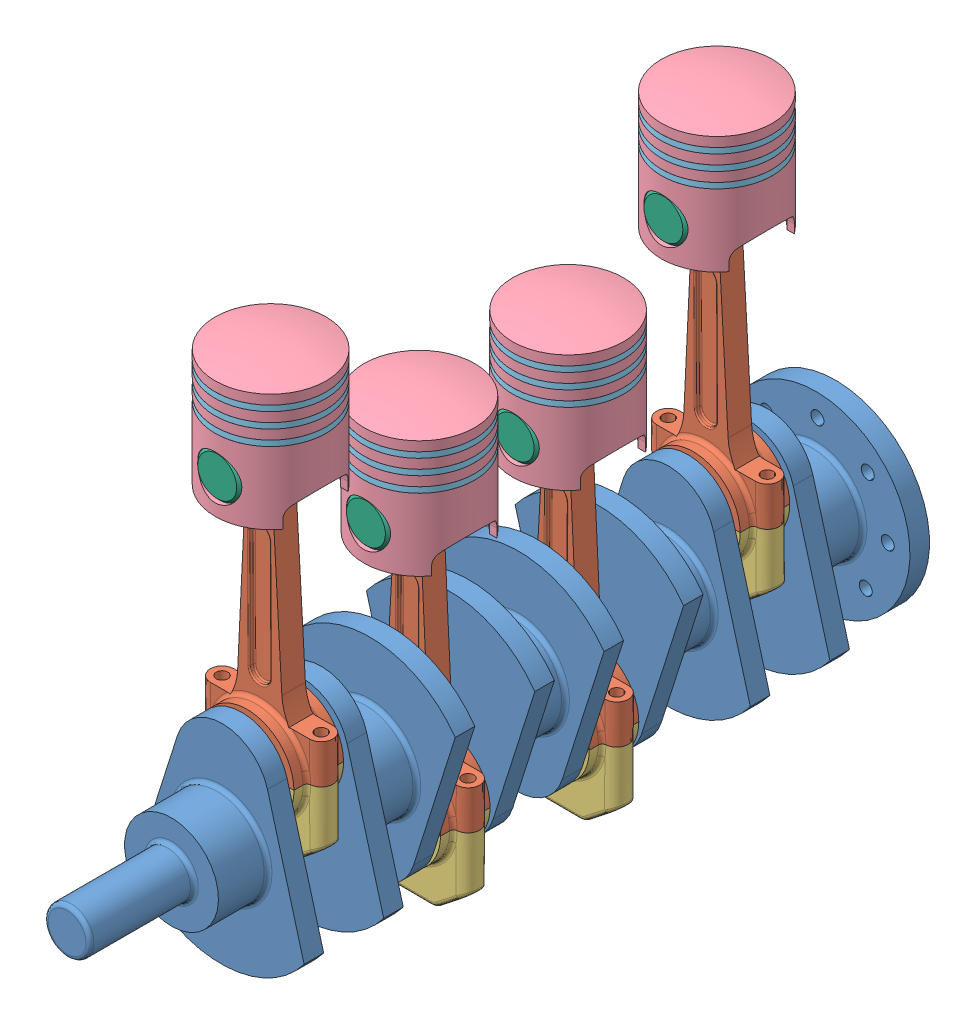
SolidWorks assembly Engine-2003091, configuration Default. Lengths in mm.
Overall size (147.06 418.41 589).
29 component instances, 6 part files, 66 mates.
Components (placement in the parent):
- Crankshaft-1: Crankshaft [Default] at (0 0 456) x (-0.999814 0.019293 0) z (0 0 1) size (144 160 589)
- Connecting rod-1: Connecting rod [Default] at (0 245.19 433) x (0.999991 0.004219 0) z (0 0 1) size (94 223.7 38)
- Connecting rod cap-1: Connecting rod cap [Default] at (0.8489 43.9918 433) x (-0.999991 -0.004219 0) z (0 0 1) size (94 60 38)
- Piston-1: Piston [Default] at (0 219.2199 433) size (85 95 85)
- Piston ring-1: Piston ring [Default] at (0 297.6199 433) size (85 4.3 85)
- Piston Pin-1: Piston Pin [Default] at (0 245.19 433) size (33.8 33.8 82)
- Piston ring-2: Piston ring [Default] at (0 286.0199 433) x (0.546944 0 -0.837169) z (0.837169 0 0.546944) size (85 4.3 85)
- Piston ring-4: Piston ring [Default] at (0 274.4199 433) x (0.546944 0 -0.837169) z (0.837169 0 0.546944) size (85 4.3 85)
- Piston-2: Piston [Default] at (0 131.2362 319) size (85 95 85)
- Piston ring-6: Piston ring [Default] at (0 209.6362 319) x (0.941458 0 -0.337131) z (0.337131 0 0.941458) size (85 4.3 85)
- Piston ring-7: Piston ring [Default] at (0 198.0362 319) x (0.23269 0 -0.972551) z (0.972551 0 0.23269) size (85 4.3 85)
- Piston ring-8: Piston ring [Default] at (0 186.4362 319) x (0.23269 0 -0.972551) z (0.972551 0 0.23269) size (85 4.3 85)
- Piston Pin-2: Piston Pin [Default] at (0 157.2064 319) x (0.216826 -0.97621 0) z (0 0 1) size (33.8 33.8 82)
- Connecting rod-2: Connecting rod [Default] at (0 157.2064 319) x (0.999991 -0.004219 0) z (0 0 1) size (94 223.7 38)
- Connecting rod cap-2: Connecting rod cap [Default] at (-0.8489 -43.9918 319) x (-0.999991 0.004219 0) z (0 0 1) size (94 60 38)
- Piston-4: Piston [Default] at (0 131.2362 205) x (-1 0 0) z (0 0 -1) size (85 95 85)
- Piston ring-12: Piston ring [Default] at (0 209.6362 205) x (0.790546 0 -0.612403) z (0.612403 0 0.790546) size (85 4.3 85)
- Piston ring-13: Piston ring [Default] at (0 198.0362 205) x (-0.0803 0 -0.996771) z (0.996771 0 -0.0803) size (85 4.3 85)
- Piston ring-14: Piston ring [Default] at (0 186.4362 205) x (-0.0803 0 -0.996771) z (0.996771 0 -0.0803) size (85 4.3 85)
- Piston Pin-4: Piston Pin [Default] at (0 157.2064 205) x (-0.34202 0.939693 0) z (0 0 -1) size (33.8 33.8 82)
- Connecting rod-4: Connecting rod [Default] at (0 157.2064 205) x (-0.999991 0.004219 0) z (0 0 -1) size (94 223.7 38)
- Connecting rod cap-4: Connecting rod cap [Default] at (-0.8489 -43.9918 205) x (0.999991 -0.004219 0) z (0 0 -1) size (94 60 38)
- Piston-6: Piston [Default] at (0 219.2199 91) x (-1 0 0) z (0 0 -1) size (85 95 85)
- Piston ring-18: Piston ring [Default] at (0 297.6199 91) x (0.6 0 -0.8) z (0.8 0 0.6) size (85 4.3 85)
- Piston ring-19: Piston ring [Default] at (0 286.0199 91) x (-0.341569 0 -0.939857) z (0.939857 0 -0.341569) size (85 4.3 85)
- Piston ring-20: Piston ring [Default] at (0 274.4199 91) x (-0.341569 0 -0.939857) z (0.939857 0 -0.341569) size (85 4.3 85)
- Piston Pin-6: Piston Pin [Default] at (0 245.19 91) x (-0.5 0.866025 0) z (0 0 -1) size (33.8 33.8 82)
- Connecting rod-6: Connecting rod [Default] at (0 245.19 91) x (-0.999991 -0.004219 0) z (0 0 -1) size (94 223.7 38)
- Connecting rod cap-6: Connecting rod cap [Default] at (0.8489 43.9918 91) x (0.999991 0.004219 0) z (0 0 -1) size (94 60 38)
Mates (geometry in assembly coordinates):
- Concentric1: concentric anti-aligned: cylinder of Crankshaft-1 through (0 0 589) axis (0 0 -1) radius 17.5
- Coincident1: coincident: plane of Crankshaft-1 through (0 0 589) normal (0 0 1)
- Coincident2: coincident aligned: plane of Piston-1 through (0 219.2199 433) normal (0 0 1); plane of Piston Pin-1 through (0 245.19 433) normal (0 0 1)
- Concentric2: concentric anti-aligned: cylinder of Piston-1 through (0 245.19 390.5) axis (0 0 1) radius 16.9; cylinder of Piston Pin-1 through (0 245.19 474) axis (0 0 -1) radius 16.9
- Concentric3: concentric aligned: cylinder of Piston-1 through (0 309.2199 433) axis (0 -1 0) radius 42.5; cylinder of Piston ring-1 through (0 301.9199 433) axis (0 -1 0) radius 42.5
- Coincident3: coincident anti-aligned: plane of Piston-1 through (0 297.6199 433) normal (0 1 0); plane of Piston ring-1 through (0 297.6199 433) normal (0 -1 0)
- Concentric4: concentric anti-aligned: cylinder of Piston-1 through (0 286.0199 433) axis (0 1 0) radius 39.5; cylinder of Piston ring-2 through (0 290.3199 433) axis (0 -1 0) radius 42.5
- Coincident4: coincident anti-aligned: plane of Piston-1 through (0 286.0199 433) normal (0 1 0); plane of Piston ring-2 through (0 286.0199 433) normal (0 -1 0)
- Concentric5: concentric anti-aligned: cylinder of Piston-1 through (0 274.4199 433) axis (0 1 0) radius 39.5; cylinder of Piston ring-4 through (0 278.7199 433) axis (0 -1 0) radius 42.5
- Coincident5: coincident anti-aligned: plane of Piston-1 through (0 274.4199 433) normal (0 1 0); plane of Piston ring-4 through (0 274.4199 433) normal (0 -1 0)
- Coincident6: coincident aligned: plane of Connecting rod-1 through (0 245.19 433) normal (0 0 1); plane of Piston-1 through (0 219.2199 433) normal (0 0 1)
- Concentric6: concentric aligned: cylinder of Connecting rod-1 through (0 245.19 452) axis (0 0 -1) radius 16.9; cylinder of Piston Pin-1 through (0 245.19 474) axis (0 0 -1) radius 16.9
- Concentric7: concentric aligned: cylinder of Connecting rod-1 through (38.8486 44.1521 433) axis (-0.004219 0.999991 0) radius 4.5; cylinder of Connecting rod cap-1 through (39.1017 -15.8473 433) axis (-0.004219 0.999991 0) radius 4.5
- Concentric8: concentric aligned: cylinder of Connecting rod-1 through (-37.1508 43.8315 433) axis (-0.004219 0.999991 0) radius 4.5; cylinder of Connecting rod cap-1 through (-36.8976 -16.168 433) axis (-0.004219 0.999991 0) radius 4.5
- Coincident7: coincident anti-aligned: plane of Connecting rod-1 through (0.8489 43.9918 452) normal (0.004219 -0.999991 0); plane of Connecting rod cap-1 through (36.8486 44.1437 452) normal (-0.004219 0.999991 0)
- Width1: width anti-aligned: plane of Crankshaft-1 through (0 0 410) normal (0 0 1); plane of Connecting rod-1 through (0 0 456) normal (0 0 -1); plane of Crankshaft-1 through (0 245.19 424) normal (0 0 -1); plane of Connecting rod-1 through (0 245.19 442) normal (0 0 1)
- Concentric9: concentric anti-aligned: cylinder of Crankshaft-1 through (0.8489 43.9918 410) axis (0 0 1) radius 27; cylinder of Connecting rod-1 through (0.8489 43.9918 452) axis (0 0 -1) radius 27
- Concentric10: concentric anti-aligned: cylinder of Piston-1 through (0 309.2199 433) axis (0 -1 0) radius 42.5
- Coincident9: coincident aligned: plane of Piston-2 through (0 131.2362 319) normal (0 0 1); plane of Piston Pin-2 through (0 157.2064 319) normal (0 0 1)
- Concentric11: concentric anti-aligned: cylinder of Piston-2 through (0 157.2064 276.5) axis (0 0 1) radius 16.9; cylinder of Piston Pin-2 through (0 157.2064 360) axis (0 0 -1) radius 16.9
- Concentric12: concentric aligned: cylinder of Piston-2 through (0 221.2362 319) axis (0 -1 0) radius 42.5; cylinder of Piston ring-6 through (0 213.9362 319) axis (0 -1 0) radius 42.5
- Coincident10: coincident anti-aligned: plane of Piston-2 through (0 209.6362 319) normal (0 1 0); plane of Piston ring-6 through (0 209.6362 319) normal (0 -1 0)
- Concentric13: concentric anti-aligned: cylinder of Piston-2 through (0 198.0362 319) axis (0 1 0) radius 39.5; cylinder of Piston ring-7 through (0 202.3362 319) axis (0 -1 0) radius 42.5
- Coincident11: coincident anti-aligned: plane of Piston-2 through (0 198.0362 319) normal (0 1 0); plane of Piston ring-7 through (0 198.0362 319) normal (0 -1 0)
- Concentric14: concentric anti-aligned: cylinder of Piston-2 through (0 186.4362 319) axis (0 1 0) radius 39.5; cylinder of Piston ring-8 through (0 190.7362 319) axis (0 -1 0) radius 42.5
- Coincident12: coincident anti-aligned: plane of Piston-2 through (0 186.4362 319) normal (0 1 0); plane of Piston ring-8 through (0 186.4362 319) normal (0 -1 0)
- Coincident13: coincident aligned: plane of Piston-2 through (0 131.2362 319) normal (0 0 1); plane of Connecting rod-2 through (0 157.2064 319) normal (0 0 1)
- Concentric15: concentric aligned: cylinder of Piston Pin-2 through (0 157.2064 360) axis (0 0 -1) radius 16.9; cylinder of Connecting rod-2 through (0 157.2064 338) axis (0 0 -1) radius 16.9
- Concentric16: concentric aligned: cylinder of Connecting rod-2 through (37.1508 -44.1521 319) axis (0.004219 0.999991 0) radius 4.5; cylinder of Connecting rod cap-2 through (36.8976 -104.1516 319) axis (0.004219 0.999991 0) radius 4.5
- Concentric17: concentric aligned: cylinder of Connecting rod-2 through (-38.8486 -43.8315 319) axis (0.004219 0.999991 0) radius 4.5; cylinder of Connecting rod cap-2 through (-39.1017 -103.8309 319) axis (0.004219 0.999991 0) radius 4.5
- Coincident14: coincident anti-aligned: plane of Connecting rod-2 through (-0.8489 -43.9918 338) normal (-0.004219 -0.999991 0); plane of Connecting rod cap-2 through (35.1508 -44.1437 338) normal (0.004219 0.999991 0)
- Width2: width anti-aligned: plane of Crankshaft-1 through (0 0 342) normal (0 0 -1); plane of Connecting rod-2 through (0 0 296) normal (0 0 1); plane of Crankshaft-1 through (0 157.2064 310) normal (0 0 -1); plane of Connecting rod-2 through (0 157.2064 328) normal (0 0 1)
- Concentric18: concentric anti-aligned: cylinder of Crankshaft-1 through (-0.8489 -43.9918 296) axis (0 0 1) radius 27; cylinder of Connecting rod-2 through (-0.8489 -43.9918 338) axis (0 0 -1) radius 27
- Concentric19: concentric anti-aligned: cylinder of Piston-2 through (0 221.2362 319) axis (0 -1 0) radius 42.5
- Coincident21: coincident aligned: plane of Piston-4 through (0 131.2362 205) normal (0 0 -1); plane of Piston Pin-4 through (0 157.2064 205) normal (0 0 -1)
- Concentric27: concentric anti-aligned: cylinder of Piston-4 through (0 157.2064 247.5) axis (0 0 -1) radius 16.9; cylinder of Piston Pin-4 through (0 157.2064 164) axis (0 0 1) radius 16.9
- Concentric28: concentric aligned: cylinder of Piston-4 through (0 221.2362 205) axis (0 -1 0) radius 42.5; cylinder of Piston ring-12 through (0 213.9362 205) axis (0 -1 0) radius 42.5
- Coincident22: coincident anti-aligned: plane of Piston-4 through (0 209.6362 205) normal (0 1 0); plane of Piston ring-12 through (0 209.6362 205) normal (0 -1 0)
- Concentric29: concentric anti-aligned: cylinder of Piston-4 through (0 198.0362 205) axis (0 1 0) radius 39.5; cylinder of Piston ring-13 through (0 202.3362 205) axis (0 -1 0) radius 42.5
- Coincident23: coincident anti-aligned: plane of Piston-4 through (0 198.0362 205) normal (0 1 0); plane of Piston ring-13 through (0 198.0362 205) normal (0 -1 0)
- Concentric30: concentric anti-aligned: cylinder of Piston-4 through (0 186.4362 205) axis (0 1 0) radius 39.5; cylinder of Piston ring-14 through (0 190.7362 205) axis (0 -1 0) radius 42.5
- Coincident24: coincident anti-aligned: plane of Piston-4 through (0 186.4362 205) normal (0 1 0); plane of Piston ring-14 through (0 186.4362 205) normal (0 -1 0)
- Coincident25: coincident aligned: plane of Piston-4 through (0 131.2362 205) normal (0 0 -1); plane of Connecting rod-4 through (0 157.2064 205) normal (0 0 -1)
- Concentric31: concentric aligned: cylinder of Piston Pin-4 through (0 157.2064 164) axis (0 0 1) radius 16.9; cylinder of Connecting rod-4 through (0 157.2064 186) axis (0 0 1) radius 16.9
- Concentric32: concentric aligned: cylinder of Connecting rod-4 through (-38.8486 -43.8315 205) axis (0.004219 0.999991 0) radius 4.5; cylinder of Connecting rod cap-4 through (-39.1017 -103.8309 205) axis (0.004219 0.999991 0) radius 4.5
- Concentric33: concentric aligned: cylinder of Connecting rod-4 through (37.1508 -44.1521 205) axis (0.004219 0.999991 0) radius 4.5; cylinder of Connecting rod cap-4 through (36.8976 -104.1516 205) axis (0.004219 0.999991 0) radius 4.5
- Coincident26: coincident anti-aligned: plane of Connecting rod-4 through (-0.8489 -43.9918 186) normal (-0.004219 -0.999991 0); plane of Connecting rod cap-4 through (-36.8486 -43.8399 186) normal (0.004219 0.999991 0)
- Width3: width anti-aligned: plane of Crankshaft-1 through (0 0 228) normal (0 0 -1); plane of Connecting rod-4 through (0 0 182) normal (0 0 1); plane of Crankshaft-1 through (0 157.2064 214) normal (0 0 1); plane of Connecting rod-4 through (0 157.2064 196) normal (0 0 -1)
- Concentric34: concentric anti-aligned: cylinder of Crankshaft-1 through (-0.8489 -43.9918 228) axis (0 0 -1) radius 27; cylinder of Connecting rod-4 through (-0.8489 -43.9918 186) axis (0 0 1) radius 27
- Concentric35: concentric anti-aligned: cylinder of Piston-4 through (0 221.2362 205) axis (0 -1 0) radius 42.5
- Coincident33: coincident aligned: plane of Piston-6 through (0 219.2199 91) normal (0 0 -1); plane of Piston Pin-6 through (0 245.19 91) normal (0 0 -1)
- Concentric43: concentric anti-aligned: cylinder of Piston-6 through (0 245.19 133.5) axis (0 0 -1) radius 16.9; cylinder of Piston Pin-6 through (0 245.19 50) axis (0 0 1) radius 16.9
- Concentric44: concentric aligned: cylinder of Piston-6 through (0 309.2199 91) axis (0 -1 0) radius 42.5; cylinder of Piston ring-18 through (0 301.9199 91) axis (0 -1 0) radius 42.5
- Coincident34: coincident anti-aligned: plane of Piston-6 through (0 297.6199 91) normal (0 1 0); plane of Piston ring-18 through (0 297.6199 91) normal (0 -1 0)
- Concentric45: concentric anti-aligned: cylinder of Piston-6 through (0 286.0199 91) axis (0 1 0) radius 39.5; cylinder of Piston ring-19 through (0 290.3199 91) axis (0 -1 0) radius 42.5
- Coincident35: coincident anti-aligned: plane of Piston-6 through (0 286.0199 91) normal (0 1 0); plane of Piston ring-19 through (0 286.0199 91) normal (0 -1 0)
- Concentric46: concentric anti-aligned: cylinder of Piston-6 through (0 274.4199 91) axis (0 1 0) radius 39.5; cylinder of Piston ring-20 through (0 278.7199 91) axis (0 -1 0) radius 42.5
- Coincident36: coincident anti-aligned: plane of Piston-6 through (0 274.4199 91) normal (0 1 0); plane of Piston ring-20 through (0 274.4199 91) normal (0 -1 0)
- Coincident37: coincident aligned: plane of Piston-6 through (0 219.2199 91) normal (0 0 -1); plane of Connecting rod-6 through (0 245.19 91) normal (0 0 -1)
- Concentric47: concentric aligned: cylinder of Piston Pin-6 through (0 245.19 50) axis (0 0 1) radius 16.9; cylinder of Connecting rod-6 through (0 245.19 72) axis (0 0 1) radius 16.9
- Concentric48: concentric aligned: cylinder of Connecting rod-6 through (-37.1508 43.8315 91) axis (-0.004219 0.999991 0) radius 4.5; cylinder of Connecting rod cap-6 through (-36.8976 -16.168 91) axis (-0.004219 0.999991 0) radius 4.5
- Concentric49: concentric aligned: cylinder of Connecting rod-6 through (38.8486 44.1521 91) axis (-0.004219 0.999991 0) radius 4.5; cylinder of Connecting rod cap-6 through (39.1017 -15.8473 91) axis (-0.004219 0.999991 0) radius 4.5
- Coincident38: coincident anti-aligned: plane of Connecting rod-6 through (0.8489 43.9918 72) normal (0.004219 -0.999991 0); plane of Connecting rod cap-6 through (-35.1508 43.8399 72) normal (-0.004219 0.999991 0)
- Width4: width anti-aligned: plane of Crankshaft-1 through (0 0 114) normal (0 0 -1); plane of Connecting rod-6 through (0 0 68) normal (0 0 1); plane of Crankshaft-1 through (0 245.19 100) normal (0 0 1); plane of Connecting rod-6 through (0 245.19 82) normal (0 0 -1)
- Concentric50: concentric anti-aligned: cylinder of Crankshaft-1 through (0.8489 43.9918 114) axis (0 0 -1) radius 27; cylinder of Connecting rod-6 through (0.8489 43.9918 72) axis (0 0 1) radius 27
- Concentric51: concentric anti-aligned: cylinder of Piston-6 through (0 309.2199 91) axis (0 -1 0) radius 42.5
